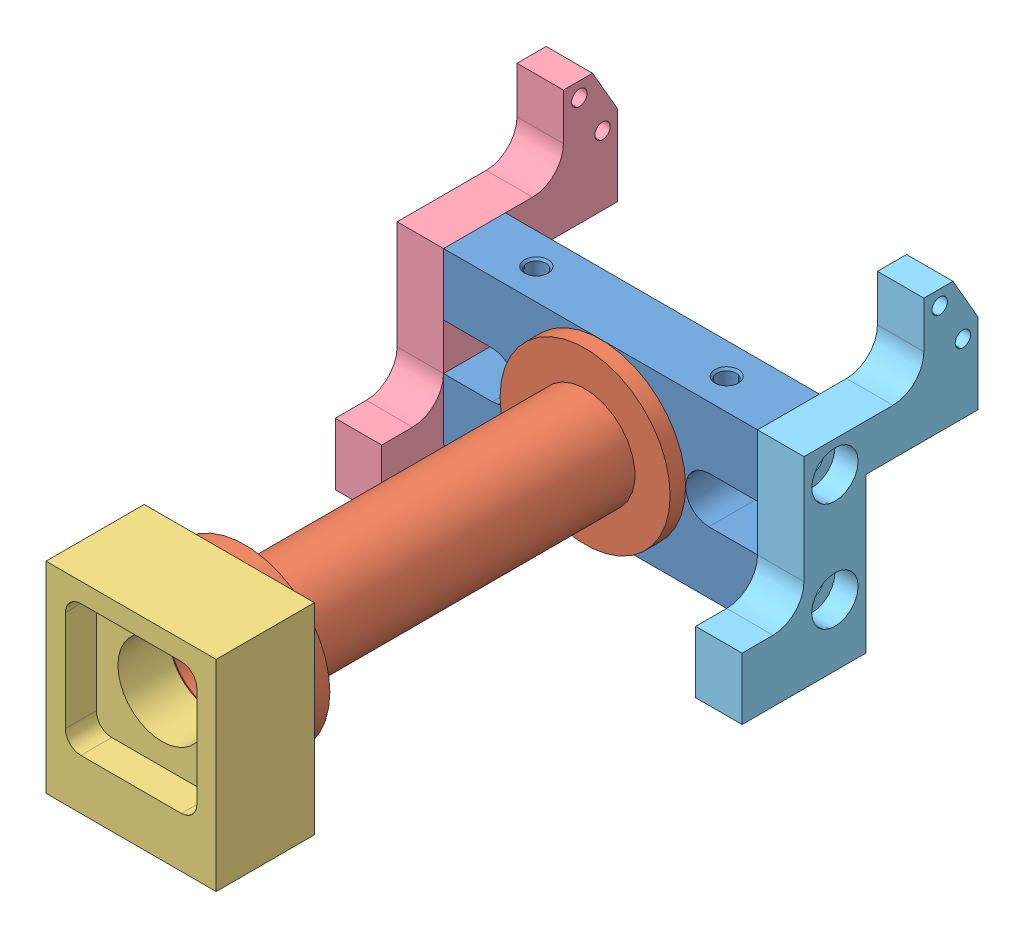
SolidWorks assembly Assem2, configuration Default. Lengths in mm.
Overall size (52.6 36 83.2).
5 component instances, 5 part files, 11 mates.
Components (placement in the parent):
- KickSolenoidFront-1: KickSolenoidFront [Default] at (-25.2108 -10.3865 -1.8255) size (40.6 22 8)
- KickSolenoid-1: KickSolenoid [Default] at (-4.9108 0.6135 4.1745) size (22 22 52)
- KickSolenoidBack-1: KickSolenoidBack [Default] at (-15.9108 -14.3865 66.8745) size (22 26 12.7)
- KickMountLeft-1: KickMountLeft [Default] at (-25.2108 -14.3865 14.1745) x (0 0 1) z (-1 0 0) size (30.5 36 6)
- KickMountRight-1: KickMountRight [Default] at (21.3892 -14.3865 14.1745) x (0 0 1) z (-1 0 0) size (30.5 36 6)
Mates (geometry in assembly coordinates):
- Concentric1: concentric aligned: cylinder of KickSolenoidFront-1 through (-4.9108 0.6135 4.0745) axis (0 0 1) radius 8.005; circle of KickSolenoid-1
- Coincident1: coincident anti-aligned: plane of KickSolenoidFront-1 through (-18.9108 0.6135 6.1745) normal (0 0 1); plane of KickSolenoid-1 through (-4.9108 0.6135 6.1745) normal (0 0 -1)
- Concentric2: concentric aligned: cylinder of KickSolenoid-1 through (-4.9108 0.6135 56.1745) axis (0 0 -1) radius 8; cylinder of KickSolenoidBack-1 through (-4.9108 0.6135 56.2745) axis (0 0 -1) radius 8.05
- Coincident2: coincident anti-aligned: plane of KickSolenoid-1 through (-4.9108 0.6135 54.1745) normal (0 0 1); plane of KickSolenoidBack-1 through (-15.9108 11.6135 54.1745) normal (0 0 -1)
- Concentric3: concentric anti-aligned: cylinder of KickSolenoidFront-1 through (15.3892 7.6135 2.1745) axis (1 0 0) radius 1.25; cylinder of KickMountLeft-1 through (-25.2108 7.6135 2.1745) axis (-1 0 0) radius 1.5
- Concentric4: concentric anti-aligned: cylinder of KickSolenoidFront-1 through (15.3892 -6.3865 2.1745) axis (1 0 0) radius 1.25; cylinder of KickMountLeft-1 through (-25.2108 -6.3865 2.1745) axis (-1 0 0) radius 1.5
- Coincident4: coincident anti-aligned: plane of KickSolenoidFront-1 through (-25.2108 3.6135 6.1745) normal (-1 0 0); plane of KickMountLeft-1 through (-25.2108 -14.3865 14.1745) normal (1 0 0)
- Concentric5: concentric aligned: cylinder of KickSolenoidFront-1 through (15.3892 7.6135 2.1745) axis (1 0 0) radius 1.25; cylinder of KickMountRight-1 through (15.3892 7.6135 2.1745) axis (1 0 0) radius 1.5
- Coincident5: coincident anti-aligned: plane of KickSolenoidFront-1 through (15.3892 3.6135 6.1745) normal (1 0 0); plane of KickMountRight-1 through (15.3892 -14.3865 14.1745) normal (-1 0 0)
- Concentric6: concentric aligned: cylinder of KickSolenoidFront-1 through (15.3892 -6.3865 2.1745) axis (1 0 0) radius 1.25; cylinder of KickMountRight-1 through (15.3892 -6.3865 2.1745) axis (1 0 0) radius 1.5
- Parallel1: parallel aligned: plane of KickSolenoidFront-1 through (-25.2108 -10.3865 6.1745) normal (0 -1 0); plane of KickSolenoidBack-1 through (-15.9108 -14.3865 66.8745) normal (0 -1 0)
